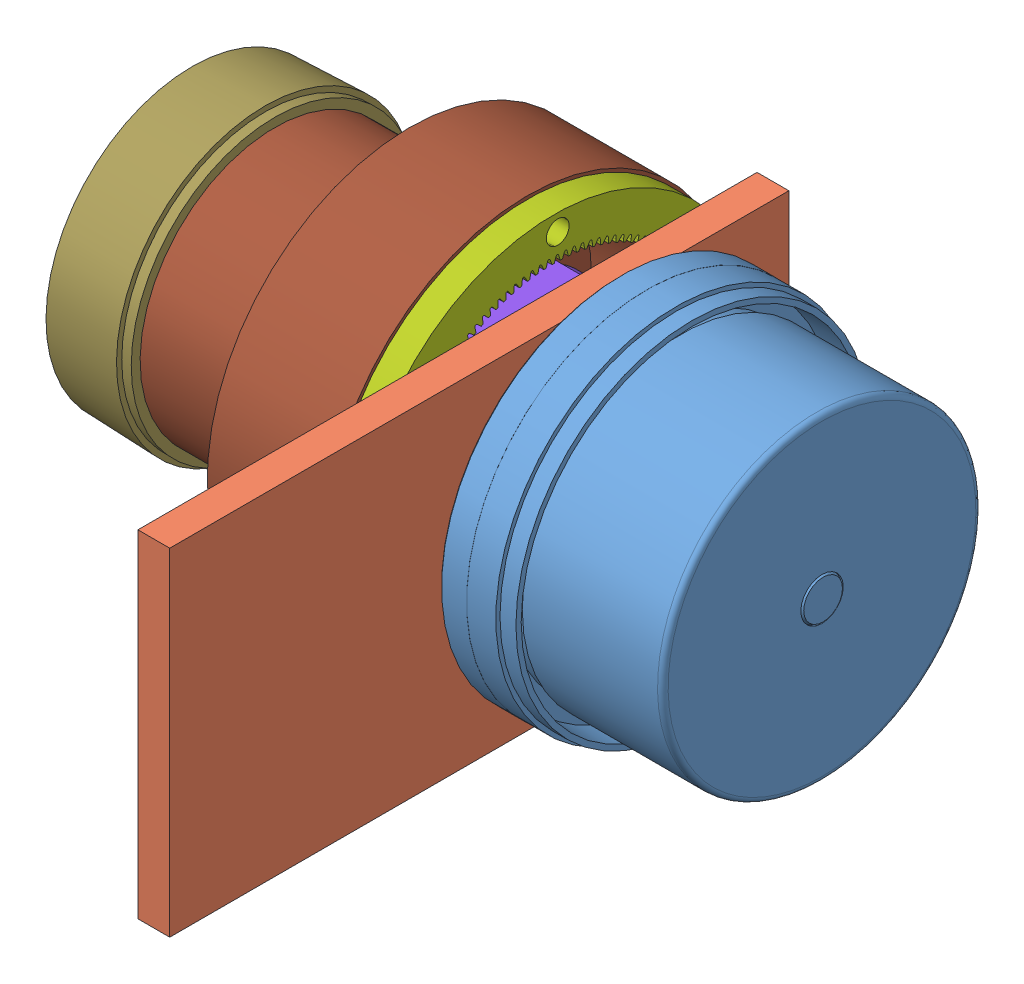
SolidWorks assembly EC60_gear_assm, configuration Default. Lengths in mm.
Overall size (119.58 385.22 134.04).
25 component instances, 16 part files, 40 mates.
Components (placement in the parent):
- EC60_motor_12_198_IP00_STEP-1: EC60_motor_12_198_IP00_STEP [Default] at (-19.22 6.3095 1.8715) size (61.3 368 68)
  - 1393671-1: 1393671 [Default] at origin size (61.3 68 68)
  - 1393806_ASM-1: 1393806_ASM [Default] at (7.3675 -28 11.51) x (0 -1 0) z (0 0 -1) size (311 10.85 10.64) (hidden)
    - 1393805-1: 1393805 [Default] at origin size (301 4.37 9.4)
    - 1393804-1: 1393804 [Default] at (296 0 11.43) x (0 0 1) z (0 1 0) size (9.85 14 10.85)
  - 1393835_ASM-1: 1393835_ASM [Default] at (10.0675 -245.4 -12.5) x (0 0 -1) z (1 0 0) size (9.68 311 14.4) (hidden)
    - 1393837-1: 1393837 [Default] at origin size (8.17 293.4 6.4)
    - 1393836-1: 1393836 [Default] at (-2.33 -79.7 -1) x (1 0 0) z (0 -1 0) size (9.6 14.4 19.6)
- link_placeholder-1: link_placeholder [Default] at (-19.22 6.3095 1.8715) x (0 0 1) z (0 -1 0) size (116.68 6 63.5)
- bearing_8mmID_mcmaster_7804K115-1: bearing_8mmID_mcmaster_7804K115 [7804K115] at (-22.97 6.3095 -15.6285) x (0 0 -1) z (1 0 0) size (12 12 3.5)
- bearing_8mmID_mcmaster_7804K115-5: bearing_8mmID_mcmaster_7804K115 [7804K115] at (-22.97 6.3095 19.3715) x (0 0 -1) z (1 0 0) size (12 12 3.5)
- carrier_shaft-1: carrier_shaft [Default] at (-19.72 6.3095 -15.6285) x (0 1 0) z (0 0 1) size (9 28.35 9)
- sun_gear_s10t05m020a0508-1: sun_gear_s10t05m020a0508 [Default] at (-34.22 6.3095 1.8715) x (1 0 0) z (0 -0.750644 0.660707) size (12.01 12.02 12)
- planet_gear_s10t05m050a0508-1: planet_gear_s10t05m050a0508 [Default] at (-34.22 6.3095 -15.6285) x (1 0 0) z (0 0.8644 -0.502804) size (12.01 26.02 25.99)
- carrier_shaft-3: carrier_shaft [Default] at (-19.72 6.3095 19.3715) x (0 1 0) z (0 0 1) size (9 28.35 9)
- planet_gear_s10t05m050a0508-2: planet_gear_s10t05m050a0508 [Default] at (-34.22 6.3095 19.3715) x (1 0 0) z (0 0.089451 0.995991) size (12.01 26.02 25.99)
- ring_gear_S1E05ZM05S120-1: ring_gear_S1E05ZM05S120 [Default] at (-34.22 6.3095 1.8715) x (1 0 0) z (0 0.02016 0.999797) size (5 75 75)
- carrier-1: carrier [Default] at (-43.07 6.3095 1.8715) x (0 0 1) z (0 -1 0) size (50.8 24.2 53.98)
- pivot_shaft-1: pivot_shaft [Default] at (-97.045 6.3095 1.8715) x (0 -0.837169 -0.546944) z (0 -0.546944 0.837169) size (22.23 53.98 22.23)
- bearing_8mmID_mcmaster_7804K115-6: bearing_8mmID_mcmaster_7804K115 [7804K115] at (-44.82 6.3095 -15.6285) x (0 1 0) z (-1 0 0) size (12 12 3.5)
- bearing_8mmID_mcmaster_7804K115-7: bearing_8mmID_mcmaster_7804K115 [7804K115] at (-44.82 6.3095 19.3715) x (0 1 0) z (-1 0 0) size (12 12 3.5)
- bearing_5-8ID_mcmaster_6383K470-1: bearing_5-8ID_mcmaster_6383K470 [6383K47] at (-75.6137 6.3095 1.8715) x (0 0.10661 -0.994301) z (1 0 0) size (38.1 38.1 11.11)
- bearing_5-8ID_mcmaster_6383K470-2: bearing_5-8ID_mcmaster_6383K470 [6383K47] at (-64.5012 6.3095 1.8715) x (0 0 -1) z (1 0 0) size (38.1 38.1 11.11)
- link2_placeholder-1: link2_placeholder [Default] at (-36.72 6.3095 1.8715) x (0 0.999797 -0.02016) z (0 0.02016 0.999797) size (76.2 47.62 76.2)
- E3-X-625-X-H-D-X-1: E3-X-625-X-H-D-X [Default] at (-87.774 6.3095 1.8715) x (0 -0.510982 0.859592) z (0 -0.859592 -0.510982) size (67.12 16.26 79.28)
Mates (geometry in assembly coordinates):
- Concentric4: concentric anti-aligned: cylinder of EC60_motor_12_198_IP00_STEP-1/1393671-1 through (-10.514 27.8095 1.8715) axis (-1 0 0) radius 1.65; cylinder of link_placeholder-1 through (-25.22 27.8095 1.8715) axis (1 0 0) radius 2
- Concentric5: concentric anti-aligned: cylinder of EC60_motor_12_198_IP00_STEP-1/1393671-1 through (-10.514 -4.4405 -16.748) axis (-1 0 0) radius 1.65; cylinder of link_placeholder-1 through (-25.22 -4.4405 -16.748) axis (1 0 0) radius 2
- Coincident15: coincident anti-aligned: plane of EC60_motor_12_198_IP00_STEP-1/1393671-1 through (-19.22 6.3095 1.8715) normal (-1 0 0); plane of link_placeholder-1 through (-19.22 -25.4405 -29.8785) normal (1 0 0)
- Coincident19: coincident anti-aligned: plane of link_placeholder-1 through (-21.22 6.3095 -15.6285) normal (-1 0 0); plane of bearing_8mmID_mcmaster_7804K115-1 through (-21.22 12.1345 -15.6285) normal (1 0 0)
- Concentric9: concentric aligned: cylinder of link_placeholder-1 through (-25.22 6.3095 -15.6285) axis (1 0 0) radius 6; cylinder of bearing_8mmID_mcmaster_7804K115-1 through (-21.22 6.3095 -15.6285) axis (1 0 0) radius 6
- Coincident21: coincident anti-aligned: plane of link_placeholder-1 through (-21.22 6.3095 19.3715) normal (-1 0 0); plane of bearing_8mmID_mcmaster_7804K115-5 through (-21.22 12.1345 19.3715) normal (1 0 0)
- Concentric10: concentric aligned: cylinder of link_placeholder-1 through (-25.22 6.3095 19.3715) axis (1 0 0) radius 6; cylinder of bearing_8mmID_mcmaster_7804K115-5 through (-21.22 6.3095 19.3715) axis (1 0 0) radius 6
- Concentric12: concentric aligned: cylinder of bearing_8mmID_mcmaster_7804K115-1 through (-21.22 6.3095 -15.6285) axis (1 0 0) radius 4; cylinder of carrier_shaft-1 through (-36.72 6.3095 -15.6285) axis (1 0 0) radius 4
- Concentric14: concentric anti-aligned: cylinder of EC60_motor_12_198_IP00_STEP-1/1393671-1 through (-45.385 6.3095 1.8715) axis (1 0 0) radius 4; cylinder of sun_gear_s10t05m020a0508-1 through (-24.12 6.3095 1.8715) axis (-1 0 0) radius 4
- Coincident22: coincident anti-aligned: plane of carrier_shaft-1 through (-36.72 6.3095 -15.6285) normal (1 0 0); plane of planet_gear_s10t05m050a0508-1 through (-36.72 6.3095 -15.6285) normal (-1 0 0)
- Concentric15: concentric anti-aligned: cylinder of carrier_shaft-1 through (-36.72 6.3095 -15.6285) axis (1 0 0) radius 4; cylinder of planet_gear_s10t05m050a0508-1 through (-24.12 6.3095 -15.6285) axis (-1 0 0) radius 4
- Coincident23: coincident aligned: plane of sun_gear_s10t05m020a0508-1 through (-36.72 6.3095 1.8715) normal (-1 0 0); plane of planet_gear_s10t05m050a0508-1 through (-36.72 6.3095 -15.6285) normal (-1 0 0)
- GearMate1: gear = 25 : 10 mm: cylinder of sun_gear_s10t05m020a0508-1 through (-24.12 6.3095 1.8715) axis (-1 0 0) radius 4; cylinder of planet_gear_s10t05m050a0508-1 through (-24.12 6.3095 -15.6285) axis (-1 0 0) radius 4
- Coincident24: coincident anti-aligned: plane of bearing_8mmID_mcmaster_7804K115-1 through (-24.72 10.4845 -15.6285) normal (-1 0 0); plane of planet_gear_s10t05m050a0508-1 through (-24.72 6.3095 -15.6285) normal (1 0 0)
- Concentric17: concentric aligned: cylinder of bearing_8mmID_mcmaster_7804K115-5 through (-21.22 6.3095 19.3715) axis (1 0 0) radius 4; cylinder of carrier_shaft-3 through (-36.72 6.3095 19.3715) axis (1 0 0) radius 4
- Concentric18: concentric anti-aligned: cylinder of carrier_shaft-3 through (-36.72 6.3095 19.3715) axis (1 0 0) radius 4; cylinder of planet_gear_s10t05m050a0508-2 through (-24.12 6.3095 19.3715) axis (-1 0 0) radius 4
- Coincident26: coincident anti-aligned: plane of carrier_shaft-3 through (-36.72 6.3095 19.3715) normal (1 0 0); plane of planet_gear_s10t05m050a0508-2 through (-36.72 6.3095 19.3715) normal (-1 0 0)
- Coincident27: coincident anti-aligned: plane of bearing_8mmID_mcmaster_7804K115-5 through (-24.72 10.4845 19.3715) normal (-1 0 0); plane of planet_gear_s10t05m050a0508-2 through (-24.72 6.3095 19.3715) normal (1 0 0)
- GearMate2: gear = 10 : 25 mm: cylinder of planet_gear_s10t05m050a0508-2 through (-24.12 6.3095 19.3715) axis (-1 0 0) radius 4; cylinder of sun_gear_s10t05m020a0508-1 through (-24.12 6.3095 1.8715) axis (-1 0 0) radius 4
- Concentric19: concentric anti-aligned: cylinder of sun_gear_s10t05m020a0508-1 through (-24.12 6.3095 1.8715) axis (-1 0 0) radius 4; cylinder of ring_gear_S1E05ZM05S120-1 through (-36.72 6.3095 1.8715) axis (1 0 0) radius 37.5
- Coincident28: coincident aligned: plane of planet_gear_s10t05m050a0508-1 through (-36.72 6.3095 -15.6285) normal (-1 0 0); plane of ring_gear_S1E05ZM05S120-1 through (-36.72 6.3095 1.8715) normal (-1 0 0)
- GearMate3: gear = 25 : 60 mm: cylinder of ring_gear_S1E05ZM05S120-1 through (-36.72 6.3095 1.8715) axis (1 0 0) radius 37.5; cylinder of planet_gear_s10t05m050a0508-2 through (-24.12 6.3095 19.3715) axis (-1 0 0) radius 4
- Concentric20: concentric anti-aligned: cylinder of carrier-1 through (-49.42 6.3095 1.8715) axis (1 0 0) radius 7.9375; cylinder of pivot_shaft-1 through (-46.245 6.3095 1.8715) axis (-1 0 0) radius 7.9375
- Coincident29: coincident anti-aligned: plane of carrier-1 through (-46.245 6.3095 1.8715) normal (1 0 0); plane of pivot_shaft-1 through (-46.245 6.3095 1.8715) normal (-1 0 0)
- Concentric21: concentric anti-aligned: cylinder of carrier-1 through (-49.42 6.3095 -15.6285) axis (1 0 0) radius 6; cylinder of bearing_8mmID_mcmaster_7804K115-6 through (-46.57 6.3095 -15.6285) axis (-1 0 0) radius 6
- Concentric22: concentric anti-aligned: cylinder of carrier-1 through (-49.42 6.3095 19.3715) axis (1 0 0) radius 6; cylinder of bearing_8mmID_mcmaster_7804K115-7 through (-46.57 6.3095 19.3715) axis (-1 0 0) radius 6
- Coincident30: coincident anti-aligned: plane of carrier-1 through (-46.57 6.3095 -15.6285) normal (1 0 0); plane of bearing_8mmID_mcmaster_7804K115-6 through (-46.57 6.3095 -21.4535) normal (-1 0 0)
- Coincident31: coincident anti-aligned: plane of carrier-1 through (-46.57 6.3095 19.3715) normal (1 0 0); plane of bearing_8mmID_mcmaster_7804K115-7 through (-46.57 6.3095 13.5465) normal (-1 0 0)
- Concentric23: concentric anti-aligned: cylinder of carrier_shaft-3 through (-48.07 6.3095 19.3715) axis (1 0 0) radius 4; cylinder of bearing_8mmID_mcmaster_7804K115-7 through (-46.57 6.3095 19.3715) axis (-1 0 0) radius 4
- Concentric24: concentric anti-aligned: cylinder of carrier_shaft-1 through (-48.07 6.3095 -15.6285) axis (1 0 0) radius 4; cylinder of bearing_8mmID_mcmaster_7804K115-6 through (-46.57 6.3095 -15.6285) axis (-1 0 0) radius 4
- Coincident32: coincident anti-aligned: plane of carrier_shaft-1 through (-43.07 6.3095 -15.6285) normal (-1 0 0); plane of bearing_8mmID_mcmaster_7804K115-6 through (-43.07 6.3095 -19.8035) normal (1 0 0)
- Concentric25: concentric anti-aligned: cylinder of pivot_shaft-1 through (-46.245 6.3095 1.8715) axis (-1 0 0) radius 7.9375; cylinder of bearing_5-8ID_mcmaster_6383K470-1 through (-70.0575 6.3095 1.8715) axis (1 0 0) radius 7.9375
- Concentric26: concentric anti-aligned: cylinder of pivot_shaft-1 through (-46.245 6.3095 1.8715) axis (-1 0 0) radius 7.9375; cylinder of bearing_5-8ID_mcmaster_6383K470-2 through (-58.945 6.3095 1.8715) axis (1 0 0) radius 7.9375
- Concentric27: concentric aligned: cylinder of bearing_5-8ID_mcmaster_6383K470-2 through (-58.945 6.3095 1.8715) axis (1 0 0) radius 19.05; cylinder of link2_placeholder-1 through (-84.345 6.3095 1.8715) axis (1 0 0) radius 19.05
- Coincident33: coincident anti-aligned: plane of bearing_5-8ID_mcmaster_6383K470-2 through (-58.945 24.8038 1.8715) normal (1 0 0); plane of link2_placeholder-1 through (-58.945 6.3095 1.8715) normal (-1 0 0)
- Concentric28: concentric aligned: circle of ring_gear_S1E05ZM05S120-1; cylinder of link2_placeholder-1 through (-49.42 40.5925 1.1803) axis (1 0 0) radius 1.6497
- Coincident34: coincident anti-aligned: plane of ring_gear_S1E05ZM05S120-1 through (-36.72 6.3095 1.8715) normal (-1 0 0); plane of link2_placeholder-1 through (-36.72 6.3095 1.8715) normal (1 0 0)
- Coincident35: coincident anti-aligned: plane of bearing_5-8ID_mcmaster_6383K470-1 through (-70.0575 18.5468 3.1836) normal (1 0 0); plane of bearing_5-8ID_mcmaster_6383K470-2 through (-70.0575 14.8026 1.8715) normal (-1 0 0)
- Concentric29: concentric aligned: cylinder of pivot_shaft-1 through (-46.245 6.3095 1.8715) axis (-1 0 0) radius 7.9375; cylinder of E3-X-625-X-H-D-X-1 through (-95.4956 6.3095 1.8715) axis (-1 0 0) radius 7.9388
- Coincident36: coincident anti-aligned: plane of link2_placeholder-1 through (-84.345 6.3095 1.8715) normal (-1 0 0); plane of E3-X-625-X-H-D-X-1 through (-84.345 15.8884 39.4343) normal (1 0 0)
